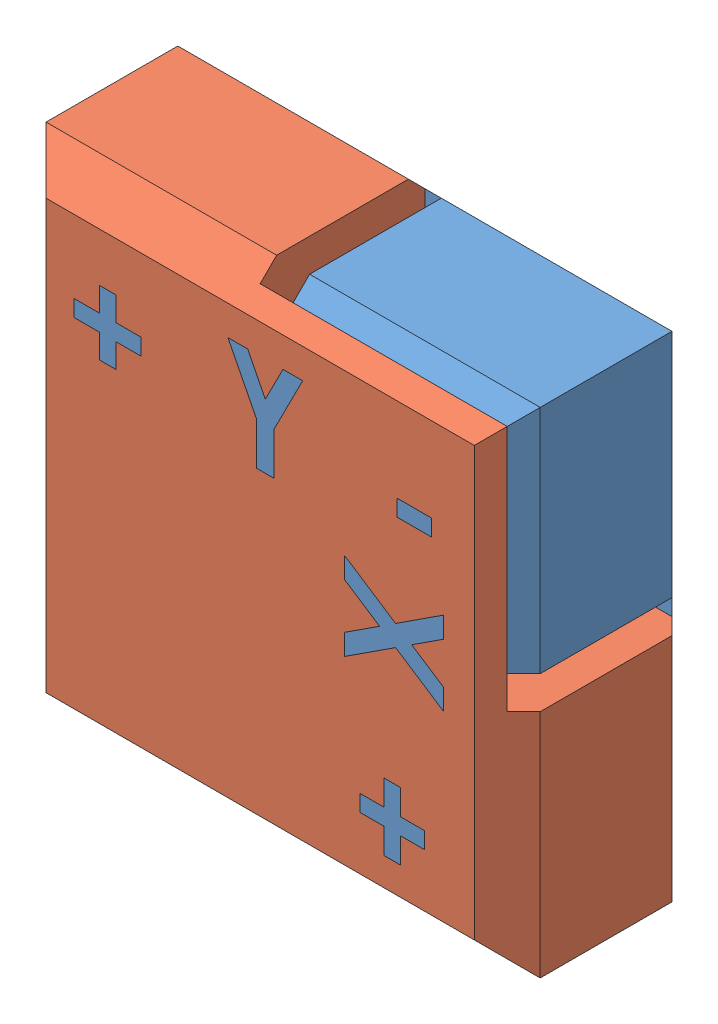
SolidWorks assembly AlignmentGauge, configuration Default. Lengths in mm.
Overall size (30 30 12).
2 component instances, 2 part files, 3 mates.
Components (placement in the parent):
- AlignmentGauge-Extruder1-1: AlignmentGauge-Extruder1 [Default] at (-7.8292 3.1658 -3.5194) size (30 30 12)
- AlignmentGauge-Extruder2-1: AlignmentGauge-Extruder2 [Default] at (-7.8292 3.1658 8.4806) x (-1 0 0) z (0 0 -1) size (30 30 11)
Mates (geometry in assembly coordinates):
- Coincident1: coincident anti-aligned: plane of AlignmentGauge-Extruder1-1 through (-7.8292 3.1658 -2.5194) normal (0 0 1); plane of AlignmentGauge-Extruder2-1 through (-7.8292 3.1658 -2.5194) normal (0 0 -1)
- Coincident2: coincident: point of AlignmentGauge-Extruder1-1; point of AlignmentGauge-Extruder2-1
- Coincident3: coincident: point of AlignmentGauge-Extruder1-1; point of AlignmentGauge-Extruder2-1
